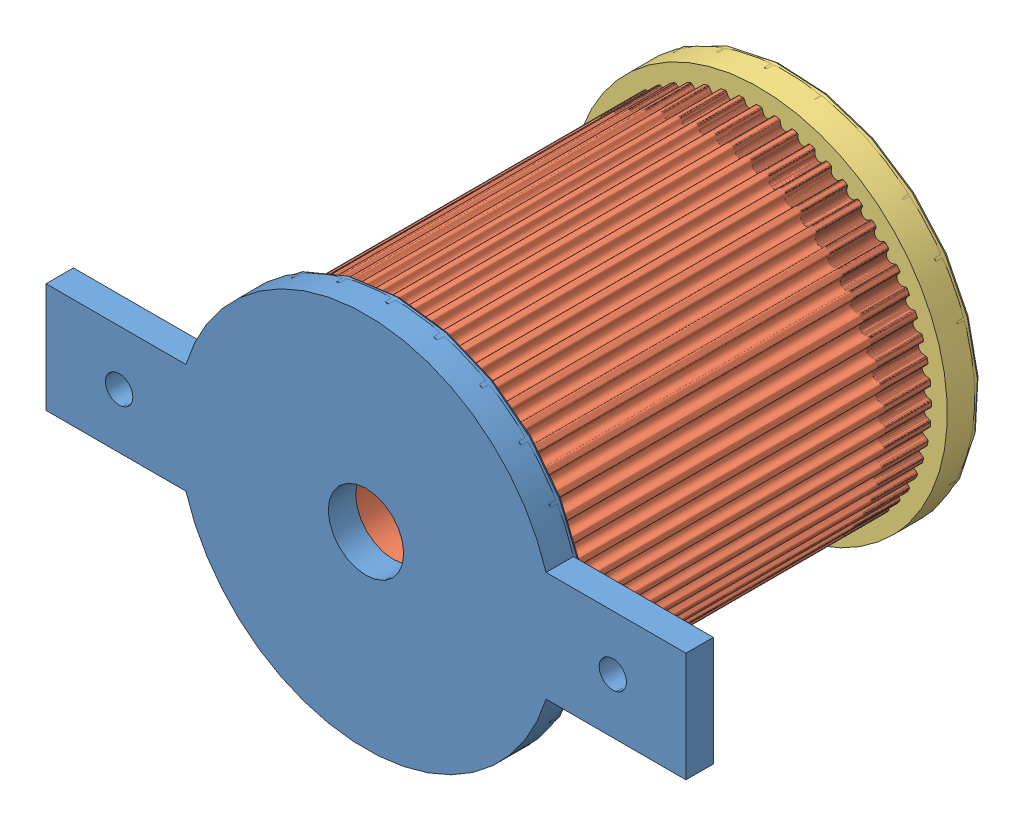
SolidWorks assembly asembly besar 40mm, configuration Default. Lengths in mm.
Overall size (70 58.07 46).
3 component instances, 3 part files, 4 mates.
Components (placement in the parent):
- Gear besar atas-1: Gear besar atas [Default] at origin size (70 41.18 4)
- puley besar 40-1: puley besar 40 [Default] at (0 0 -43) size (37.7 37.7 44)
- Gear besar bawah-1: Gear besar bawah [Default] at (0 0 -43) x (0.758977 -0.651118 0) z (0 0 1) size (41.18 41.18 4)
Mates (geometry in assembly coordinates):
- Concentric1: concentric aligned: cylinder of Gear besar atas-1 through (0 0 4) axis (0 0 -1) radius 4.125; cylinder of puley besar 40-1 through (0 0 1) axis (0 0 -1) radius 4.125
- Concentric2: concentric aligned: cylinder of puley besar 40-1 through (0 0 1) axis (0 0 -1) radius 4.125; cylinder of Gear besar bawah-1 through (0 0 -39) axis (0 0 -1) radius 4.125
- Coincident1: coincident anti-aligned: plane of puley besar 40-1 through (-14.9087 -11.3035 -39) normal (0 0 -1); plane of Gear besar bawah-1 through (0 0 -39) normal (0 0 1)
- Coincident2: coincident anti-aligned: plane of Gear besar atas-1 through (0 0 1) normal (0 0 -1); plane of puley besar 40-1 through (-14.9087 -11.3035 1) normal (0 0 1)
